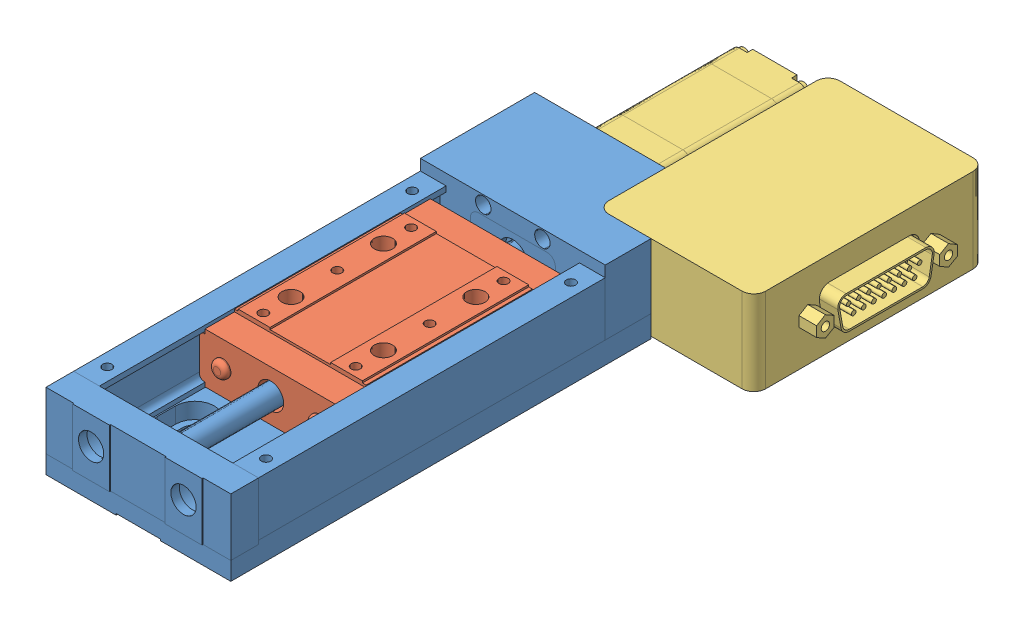
SolidWorks assembly LRM, configuration LRM025x-T3A. Lengths in mm.
Overall size (82.57 23.48 176.5).
3 component instances, 3 part files, 3 mates.
Components (placement in the parent):
- LRM_base^LRM-1: LRM_base^LRM [LRM025] at origin size (50 23.48 132.5) (virtual)
- LRM_carriage^LRM-1: LRM_carriage^LRM [LRM] at origin size (38.6 14.7 64) (virtual)
- NMS08_motor^LRM-1: NMS08_motor^LRM [LRM-T3A] at origin size (67.57 22.9 62.5) (virtual)
Mates (geometry in assembly coordinates):
- Coincident1: coincident aligned: plane of LRM_carriage^LRM-1 through (0 0 0) normal (1 0 0); plane of assembly through (0 0 0) normal (1 0 0)
- Coincident2: coincident aligned: plane of LRM_carriage^LRM-1 through (0 0 0) normal (0 1 0); plane of assembly through (0 0 0) normal (0 1 0)
- LimitDistance1: limit distance = 0 mm aligned: plane of LRM_carriage^LRM-1 through (0 0 0) normal (0 0 1); plane of assembly through (0 0 0) normal (0 0 1)
